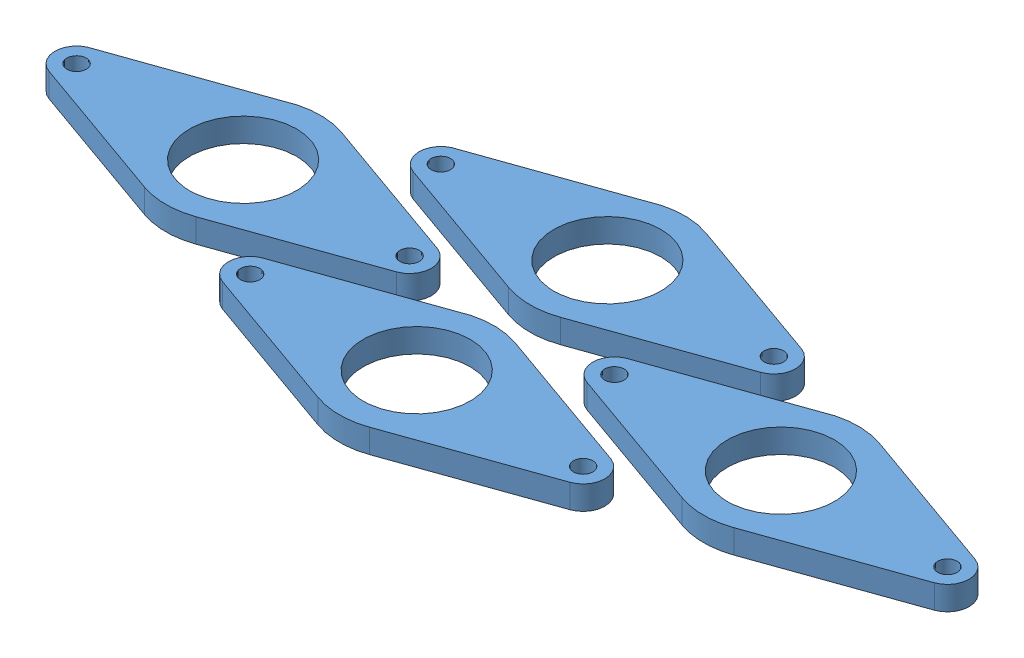
SolidWorks assembly Assem1, configuration Default. Lengths in mm.
Overall size (244.11 6.35 92.15).
4 component instances, 1 part files, 0 mates.
Components (placement in the parent):
- Shaft Support-1: Shaft Support [Default] at (36.7664 44.815 82.6556) size (100.45 6.35 41.27)
- Shaft Support-2: Shaft Support [Default] at (-35.0478 44.815 57.177) size (100.45 6.35 41.27)
- Shaft Support-3: Shaft Support [Default] at (-35.0779 44.815 108.0491) size (100.45 6.35 41.27)
- Shaft Support-4: Shaft Support [Default] at (-106.8922 44.815 82.5706) size (100.45 6.35 41.27)
